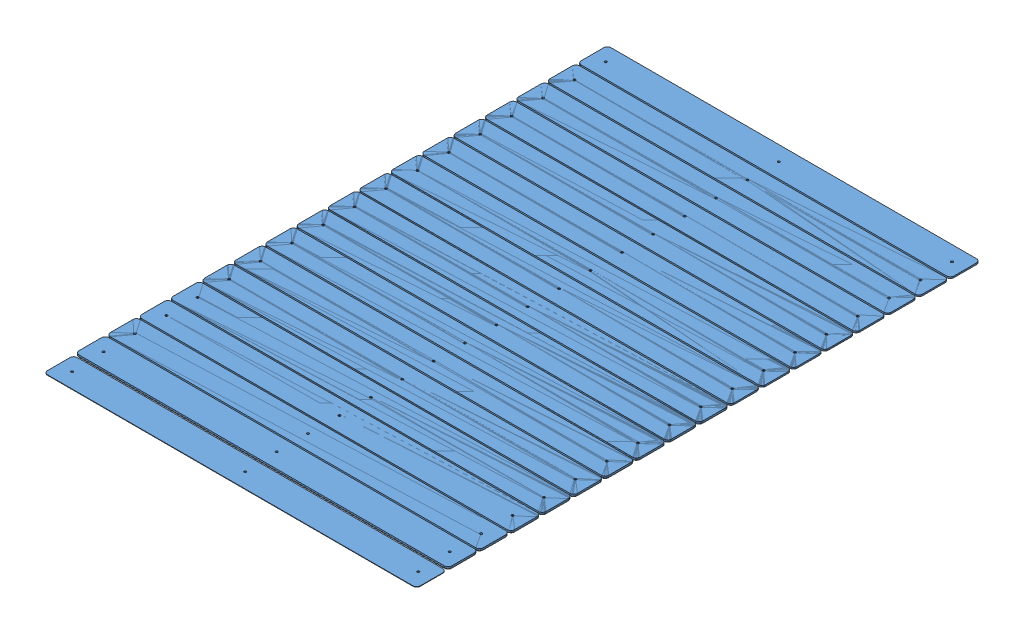
SolidWorks assembly backstrip_array, configuration Default. Lengths in mm.
Overall size (633.55 3.33 957.79).
10 component instances, 1 part files, 0 mates.
Components (placement in the parent):
- 1_hold_plate-1: 1_hold_plate [Default] at (-24.3903 7.6807 7.3826) size (633.55 3.33 477.73)
- 1_hold_plate-2: 1_hold_plate [Default] at (-24.3903 7.6807 60.7226) size (633.55 3.33 477.73)
- 1_hold_plate-3: 1_hold_plate [Default] at (-24.3903 7.6807 114.0626) size (633.55 3.33 477.73)
- 1_hold_plate-4: 1_hold_plate [Default] at (-24.3903 7.6807 167.4026) size (633.55 3.33 477.73)
- 1_hold_plate-5: 1_hold_plate [Default] at (-24.3903 7.6807 220.7426) size (633.55 3.33 477.73)
- 1_hold_plate-6: 1_hold_plate [Default] at (-24.3903 7.6807 274.0826) size (633.55 3.33 477.73)
- 1_hold_plate-7: 1_hold_plate [Default] at (-24.3903 7.6807 327.4226) size (633.55 3.33 477.73)
- 1_hold_plate-8: 1_hold_plate [Default] at (-24.3903 7.6807 380.7626) size (633.55 3.33 477.73)
- 1_hold_plate-9: 1_hold_plate [Default] at (-24.3903 7.6807 434.1026) size (633.55 3.33 477.73)
- 1_hold_plate-10: 1_hold_plate [Default] at (-24.3903 7.6807 487.4426) size (633.55 3.33 477.73)
